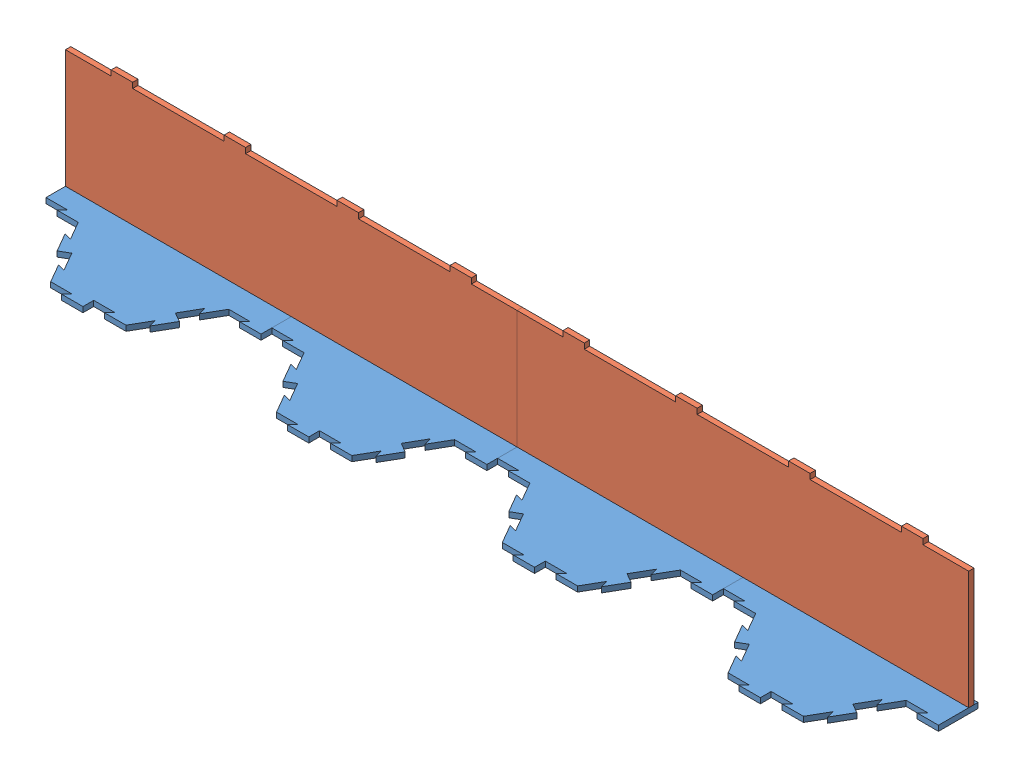
SolidWorks assembly wall_full_assembly, configuration Default. Lengths in mm.
Overall size (1066.8 152.4 123.67).
4 component instances, 2 part files, 9 mates.
Components (placement in the parent):
- border_bigger-1: border_bigger [Default] at origin size (533.4 6.35 123.67)
- wall_full-1: wall_full [Default] at (133.35 69.85 -29.3294) x (1 0 0) z (0 1 0) size (533.4 6.35 152.4)
- border_bigger-2: border_bigger [Default] at (533.4 0 0) size (533.4 6.35 123.67)
- wall_full-3: wall_full [Default] at (666.75 69.85 -29.3294) x (1 0 0) z (0 1 0) size (533.4 6.35 152.4)
Mates (geometry in assembly coordinates):
- Coincident1: coincident anti-aligned: plane of border_bigger-1 through (-79.375 -6.35 -35.6794) normal (1 0 0); plane of wall_full-1 through (-79.375 0 -29.3294) normal (-1 0 0)
- Coincident2: coincident anti-aligned: plane of border_bigger-1 through (-79.375 -6.35 -29.3294) normal (0 0 -1); plane of wall_full-1 through (133.35 69.85 -29.3294) normal (0 0 1)
- Coincident3: coincident aligned: plane of border_bigger-1 through (0 -6.35 0) normal (0 -1 0); plane of wall_full-1 through (-133.35 -6.35 -35.6794) normal (0 -1 0)
- Coincident4: coincident anti-aligned: plane of border_bigger-1 through (400.05 -6.35 -40.3279) normal (1 0 0); plane of border_bigger-2 through (400.05 -6.35 -40.3279) normal (-1 0 0)
- Coincident5: coincident aligned: plane of border_bigger-1 through (266.7 0 -40.3279) normal (0 0 -1); plane of border_bigger-2 through (533.4 0 -40.3279) normal (0 0 -1)
- Coincident6: coincident aligned: plane of border_bigger-1 through (266.7 0 0) normal (0 1 0); plane of border_bigger-2 through (533.4 0 0) normal (0 1 0)
- Coincident10: coincident anti-aligned: plane of border_bigger-2 through (454.025 -6.35 -35.6794) normal (1 0 0); plane of wall_full-3 through (454.025 0 -29.3294) normal (-1 0 0)
- Coincident11: coincident anti-aligned: plane of border_bigger-2 through (454.025 -6.35 -29.3294) normal (0 0 -1); plane of wall_full-3 through (666.75 69.85 -29.3294) normal (0 0 1)
- Coincident12: coincident aligned: plane of border_bigger-2 through (533.4 -6.35 0) normal (0 -1 0); plane of wall_full-3 through (400.05 -6.35 -35.6794) normal (0 -1 0)
